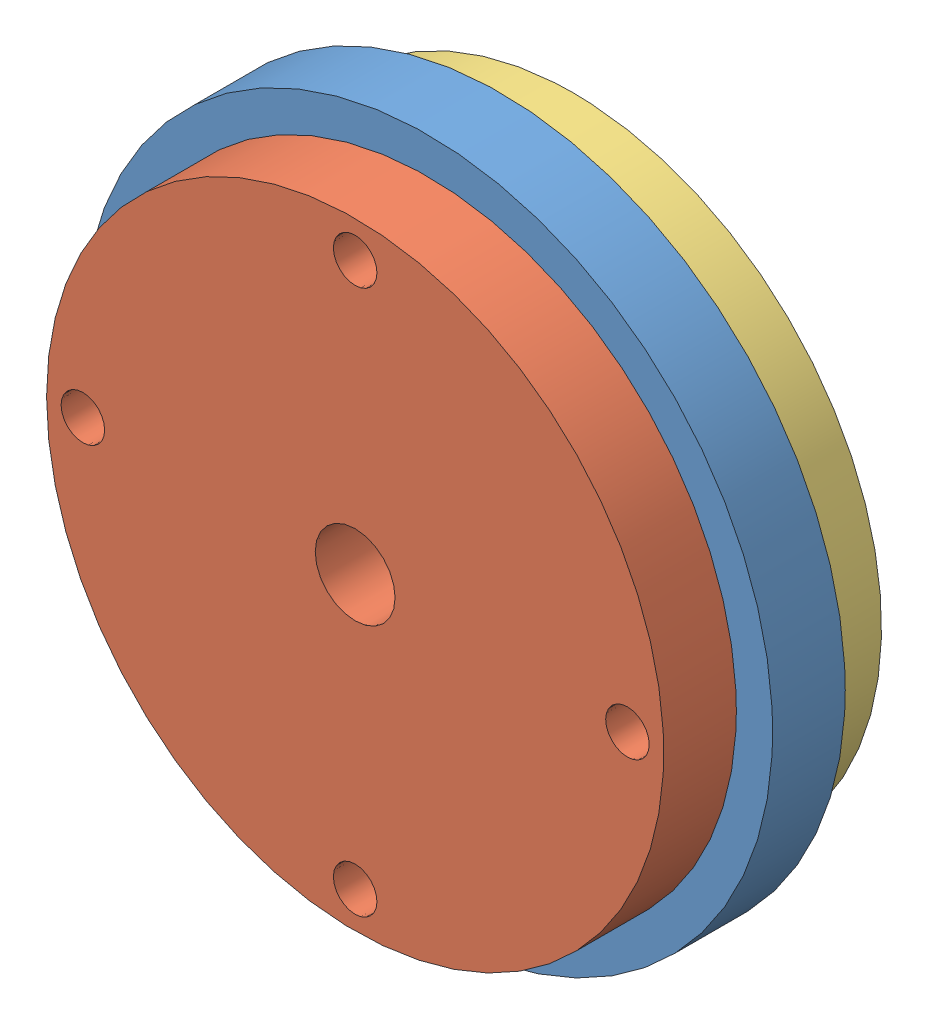
SolidWorks assembly Assemblage1, configuration Défaut. Lengths in mm.
Overall size (9.5 9.5 3).
3 component instances, 3 part files, 4 mates.
Components (placement in the parent):
- pignon sans pigon-1: pignon sans pigon [Défaut] at (4.7797 0.4366 6.9138) size (9.5 9.5 1)
- cu-1: cu [Défaut] at (4.7797 0.4366 7.9138) size (8.5 8.5 1)
- rotor-1: rotor [Défaut] at (4.7797 0.4366 6.9138) x (1 0 0) z (0 1 0) size (8.5 1 8.5)
Mates (geometry in assembly coordinates):
- Coïncidente1: coincident: circle of pignon sans pigon-1; circle of rotor-1
- Coïncidente2: coincident anti-aligned: circle of pignon sans pigon-1; circle of rotor-1
- Coïncidente3: coincident: circle of pignon sans pigon-1; circle of cu-1
- Coïncidente4: coincident aligned: circle of pignon sans pigon-1; circle of cu-1
